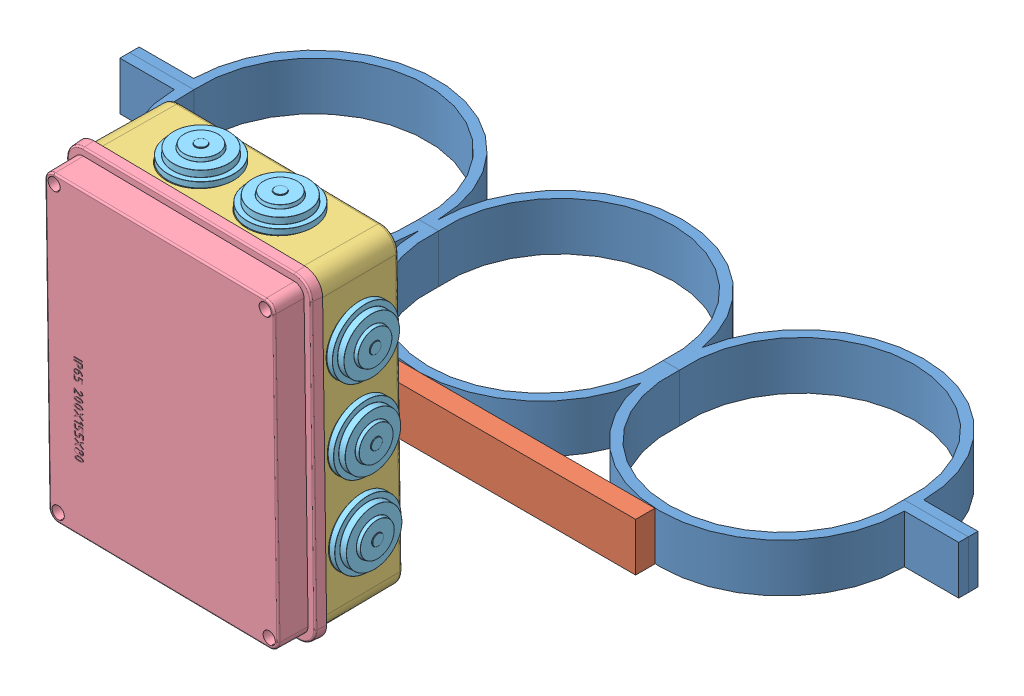
SolidWorks assembly 装配体1, configuration 默认. Lengths in mm.
Overall size (521.32 215.74 255.68).
21 component instances, 7 part files, 7 mates.
Components (placement in the parent):
- 零件1-1: 零件1 [默认] at (-9.6173 42.3571 486.3207) size (521.32 30 82)
- 零件1-2: 零件1 [默认] at (-9.6173 72.3571 474.3207) x (1 0 0) z (0 0 -1) size (521.32 30 82)
- 零件2-1: 零件2 [默认] at (-14.8998 42.3571 588.3778) x (1 0 0) z (0 1 0) size (304 12 30)
- IP65 ELECTRICAL ENCLOSURE, 200 mm x 155 mm x 80 mm-1: IP65 ELECTRICAL ENCLOSURE, 200 mm x 155 mm x 80 mm [默认] at (-79.5981 61.2464 577.0465) x (0.000193 -0.999904 -0.013884) z (-0.999904 0 -0.013885) size (214.7 76.3 169.68)
  - ENCLOSURE, IP65 ELECTRICAL ENCLOSURE, 200 mm x 155 mm x 80 mm_1-1: ENCLOSURE, IP65 ELECTRICAL ENCLOSURE, 200 mm x 155 mm x 80 mm_1 [默认] at origin size (197.16 54.12 152.16)
  - ENCLOSURE COVER, IP65 ELECTRICAL ENCLOSURE, 200 mm x 155 mm x 80 mm_1-1: ENCLOSURE COVER, IP65 ELECTRICAL ENCLOSURE, 200 mm x 155 mm x 80 mm_1 [默认] at (0 49.6 0) size (200 24.71 155)
  - GROMMET, IP65 ELECTRICAL ENCLOSURE, 200 mm x 155 mm x 80 mm_1-1: GROMMET, IP65 ELECTRICAL ENCLOSURE, 200 mm x 155 mm x 80 mm_1 [默认] at (0 24.6073 66.8362) x (-0.999687 0.025034 0.000241) z (0 -0.009615 0.999954) size (41 41 17.8)
  - GROMMET, IP65 ELECTRICAL ENCLOSURE, 200 mm x 155 mm x 80 mm_1-2: GROMMET, IP65 ELECTRICAL ENCLOSURE, 200 mm x 155 mm x 80 mm_1 [默认] at (52 24.6073 66.8362) x (-0.999687 0.025034 0.000241) z (0 -0.009615 0.999954) size (41 41 17.8)
  - GROMMET, IP65 ELECTRICAL ENCLOSURE, 200 mm x 155 mm x 80 mm_1-3: GROMMET, IP65 ELECTRICAL ENCLOSURE, 200 mm x 155 mm x 80 mm_1 [默认] at (-52 24.6073 66.8362) x (-0.999687 0.025034 0.000241) z (0 -0.009615 0.999954) size (41 41 17.8)
  - GROMMET, IP65 ELECTRICAL ENCLOSURE, 200 mm x 155 mm x 80 mm_1-4: GROMMET, IP65 ELECTRICAL ENCLOSURE, 200 mm x 155 mm x 80 mm_1 [默认] at (0 24.6073 -66.8362) x (0.999687 -0.025034 0.000241) z (0 -0.009615 -0.999954) size (41 41 17.8)
  - GROMMET, IP65 ELECTRICAL ENCLOSURE, 200 mm x 155 mm x 80 mm_1-5: GROMMET, IP65 ELECTRICAL ENCLOSURE, 200 mm x 155 mm x 80 mm_1 [默认] at (52 24.6073 -66.8362) x (0.999687 -0.025034 0.000241) z (0 -0.009615 -0.999954) size (41 41 17.8)
  - GROMMET, IP65 ELECTRICAL ENCLOSURE, 200 mm x 155 mm x 80 mm_1-6: GROMMET, IP65 ELECTRICAL ENCLOSURE, 200 mm x 155 mm x 80 mm_1 [默认] at (-52 24.6073 -66.8362) x (0.999687 -0.025034 0.000241) z (0 -0.009615 -0.999954) size (41 41 17.8)
  - GROMMET, IP65 ELECTRICAL ENCLOSURE, 200 mm x 155 mm x 80 mm_1-7: GROMMET, IP65 ELECTRICAL ENCLOSURE, 200 mm x 155 mm x 80 mm_1 [默认] at (89.3342 24.391 -25) x (-0.009571 -0.995424 -0.095073) z (0.999954 -0.009615 0) size (41 41 17.8)
  - GROMMET, IP65 ELECTRICAL ENCLOSURE, 200 mm x 155 mm x 80 mm_1-8: GROMMET, IP65 ELECTRICAL ENCLOSURE, 200 mm x 155 mm x 80 mm_1 [默认] at (89.3342 24.391 25) x (0.009571 0.995424 -0.095073) z (0.999954 -0.009615 0) size (41 41 17.8)
  - GROMMET, IP65 ELECTRICAL ENCLOSURE, 200 mm x 155 mm x 80 mm_1-9: GROMMET, IP65 ELECTRICAL ENCLOSURE, 200 mm x 155 mm x 80 mm_1 [默认] at (-89.3342 24.391 -25) x (-0.009571 0.995424 0.095073) z (-0.999954 -0.009615 0) size (41 41 17.8)
  - GROMMET, IP65 ELECTRICAL ENCLOSURE, 200 mm x 155 mm x 80 mm_1-10: GROMMET, IP65 ELECTRICAL ENCLOSURE, 200 mm x 155 mm x 80 mm_1 [默认] at (-89.3342 24.391 25) x (0.009571 -0.995424 0.095073) z (-0.999954 -0.009615 0) size (41 41 17.8)
  - O-RING, IP65 ELECTRICAL ENCLOSURE, 200 mm x 155 mm x 80 mm_1-1: O-RING, IP65 ELECTRICAL ENCLOSURE, 200 mm x 155 mm x 80 mm_1 [默认] at (0 52.1 0) x (1 0 0) z (0 -1 0) size (195 150 3)
  - cross ph tapping 968_din_Screw DIN 968-ST2.9x13-C-H-N-1: cross ph tapping 968_din_Screw DIN 968-ST2.9x13-C-H-N [默认] at (-89 54.1 66.5) x (0 -1 0) z (-0.071053 0 0.997473) size (15.35 7.5 7.5)
  - cross ph tapping 968_din_Screw DIN 968-ST2.9x13-C-H-N-2: cross ph tapping 968_din_Screw DIN 968-ST2.9x13-C-H-N [默认] at (89 54.1 66.5) x (0 -1 0) z (-0.071053 0 -0.997473) size (15.35 7.5 7.5)
  - cross ph tapping 968_din_Screw DIN 968-ST2.9x13-C-H-N-3: cross ph tapping 968_din_Screw DIN 968-ST2.9x13-C-H-N [默认] at (-89 54.1 -66.5) x (0 -1 0) z (0.071053 0 0.997473) size (15.35 7.5 7.5)
  - cross ph tapping 968_din_Screw DIN 968-ST2.9x13-C-H-N-4: cross ph tapping 968_din_Screw DIN 968-ST2.9x13-C-H-N [默认] at (89 54.1 -66.5) x (0 -1 0) z (0.071053 0 -0.997473) size (15.35 7.5 7.5)
Mates (geometry in assembly coordinates):
- 重合1: coincident anti-aligned: plane of 零件1-1 through (-271.4346 72.3571 480.3207) normal (0 0 -1); plane of 零件1-2 through (-271.4346 42.3571 480.3207) normal (0 0 1)
- 重合2: coincident aligned: plane of 零件1-1 through (-271.4346 72.3571 486.3207) normal (-1 0 0); plane of 零件1-2 through (-271.4346 42.3571 474.3207) normal (-1 0 0)
- 重合3: coincident aligned: plane of 零件1-1 through (-161.6101 72.3571 485.2739) normal (0 1 0); plane of 零件1-2 through (-161.6101 72.3571 475.3675) normal (0 1 0)
- 重合4: coincident aligned: plane of 零件1-1 through (-161.6101 42.3571 485.2739) normal (0 -1 0); plane of 零件2-1 through (-14.8998 42.3571 588.3778) normal (0 -1 0)
- 平行1: parallel aligned: plane of 零件1-1 through (249.8861 72.3571 486.3207) normal (1 0 0); plane of 零件2-1 through (137.1002 72.3571 562.3207) normal (1 0 0)
- 相切3: tangent anti-aligned: cylinder of 零件1-1 through (140.1437 72.3571 486.3207) axis (0 -1 0) radius 76; plane of 零件2-1 through (-166.8998 72.3571 562.3207) normal (0 0 -1)
- 平行7: parallel anti-aligned: plane of 零件2-1 through (-14.8998 72.3571 588.3778) normal (0 1 0); plane of IP65 ELECTRICAL ENCLOSURE, 200 mm x 155 mm x 80 mm-1/ENCLOSURE COVER, IP65 ELECTRICAL ENCLOSURE, 200 mm x 155 mm x 80 mm_1-1 through (-146.8523 -34.5234 630.8934) normal (0 -1 0)
